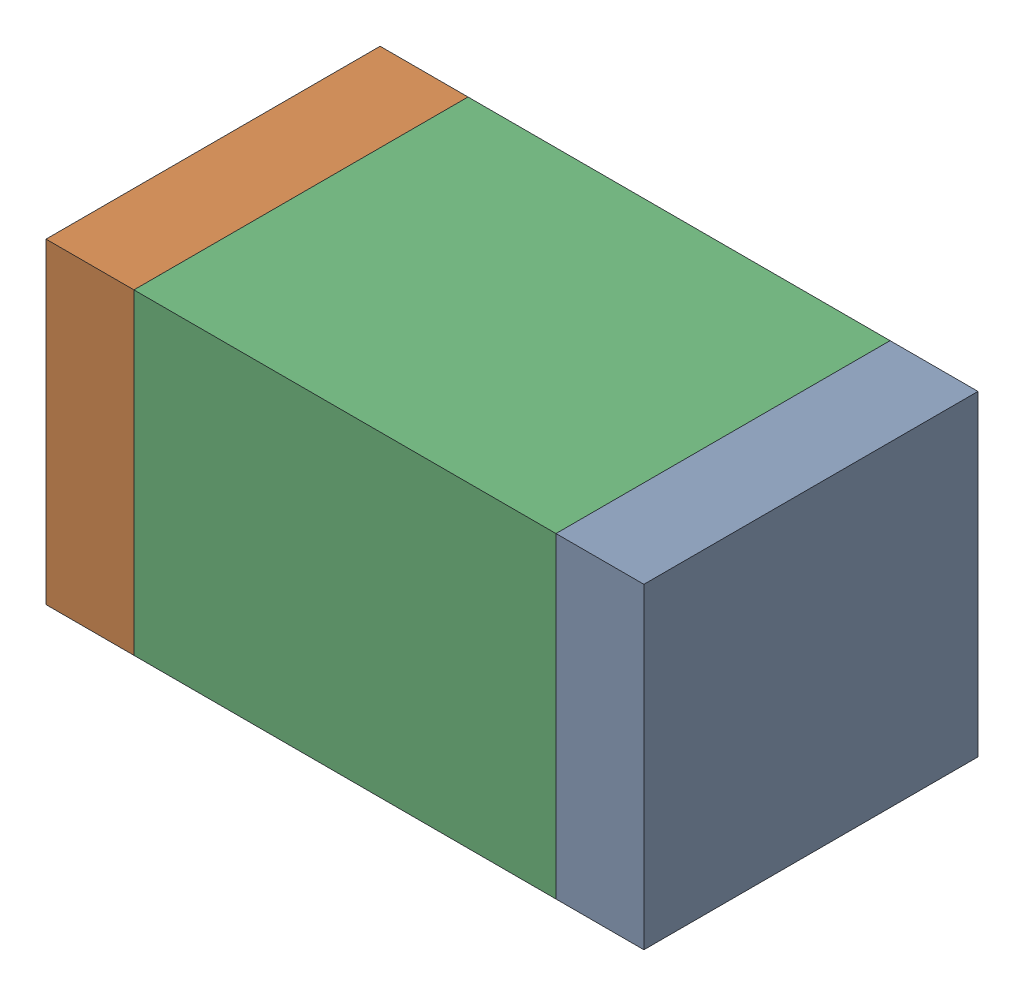
SolidWorks assembly C1, configuration Default. Lengths in mm.
Overall size (3.4 1.8 1.9).
6 component instances, 2 part files, 0 mates.
Components (placement in the parent):
- 959208392-1: 959208392 [Default] at (133.022 83.687 0) size (0.5 1.8 1.9)
  - Extruded-12-1: Extruded-12 [Default] at origin size (0.5 1.8 1.9)
- 959208392-2: 959208392 [Default] at (130.122 83.687 0) size (0.5 1.8 1.9)
  - Extruded-12-1: Extruded-12 [Default] at origin size (0.5 1.8 1.9)
- 959208256-1: 959208256 [Default] at (131.572 83.687 0) size (2.4 1.8 1.9)
  - Extruded-13-1: Extruded-13 [Default] at origin size (2.4 1.8 1.9)
